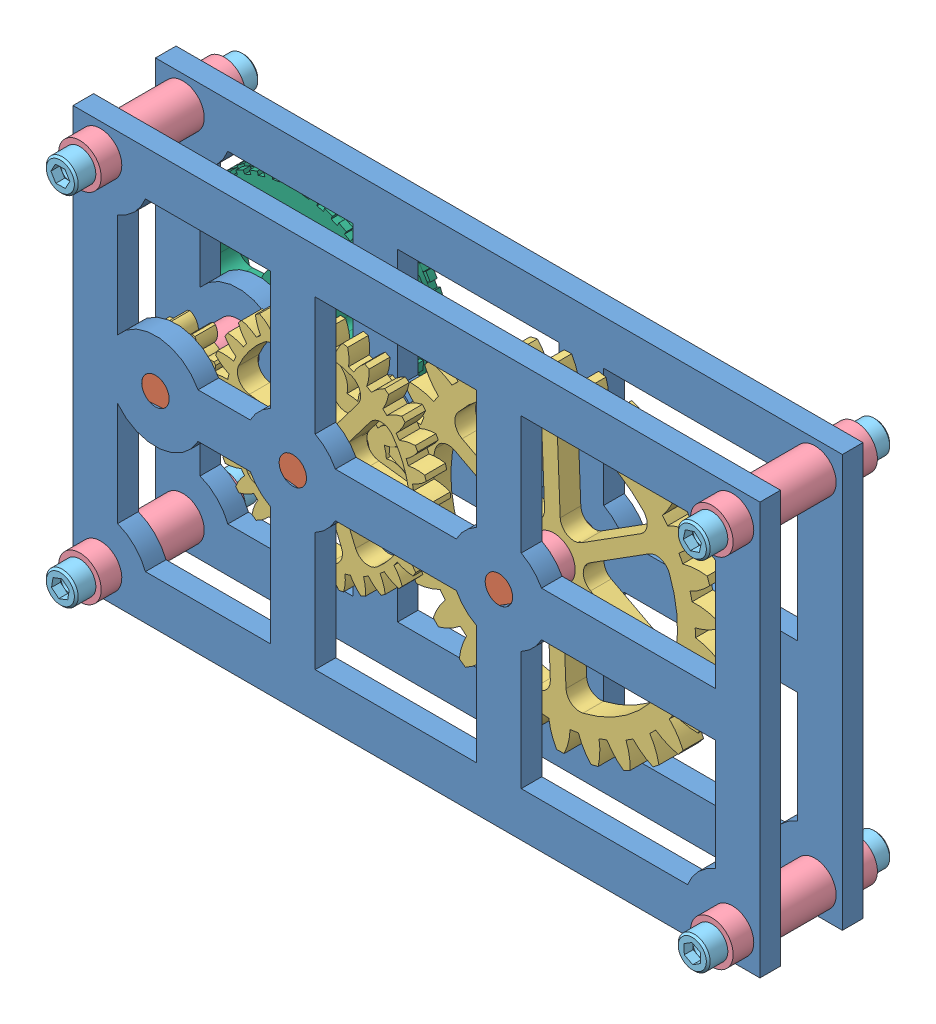
SolidWorks assembly gear_box, configuration Default. Lengths in mm.
Overall size (105.06 66.08 32.84).
42 component instances, 6 part files, 60 mates.
Components (placement in the parent):
- plate-1: plate [Default] at (41.197 56.7487 70.1164) size (100 60 3)
- assem_2-1: assem_2 [Default] at (31.1022 63.8399 66.8559) x (-0.992322 0.123679 0) z (0 0 1) size (32 31.89 15)
  - axle-1: axle [15mm] at (6.9674 8.0145 3.2605) size (4 3.72 15)
  - root_gear-1: root_gear [30T 1.0Mod] at (6.9674 8.0145 11.2605) size (32 31.89 3)
  - root_gear-2: root_gear [10T 1.5Mod] at (6.9674 8.0145 7.2605) size (18 17.3 3)
  - spacer-1: spacer [4.2mm ID 1L] at (6.9674 8.0145 6.2605) size (6.2 6.2 1)
  - spacer-2: spacer [4.2mm ID 1L] at (6.9674 8.0145 14.2605) x (0.300873 0.953664 0) z (0 0 1) size (6.2 6.2 1)
  - spacer-3: spacer [4.2mm ID 1L] at (6.9674 8.0145 10.2605) x (0.999497 0.031723 0) z (0 0 1) size (6.2 6.2 1)
- Assem3-1: Assem3 [Default] at (37.7796 60.6091 98.5469) x (0.845417 0.534107 0) z (0 0 -1) size (48 47.84 15)
  - spacer-1: spacer [4.2mm ID 1L] at (10.9723 11.4982 24.4305) x (0.97362 0.228174 0) z (0 0 1) size (6.2 6.2 1)
  - spacer-2: spacer [4.2mm ID 5L] at (10.9723 11.4982 16.4305) x (0.545669 0.838001 0) z (0 0 1) size (6.2 6.2 5)
  - root_gear-1: root_gear [30T 1.5Mod] at (10.9723 11.4982 21.4305) size (48 47.84 3)
  - axle-2: axle [15mm] at (10.9723 11.4982 13.4305) size (4 3.72 15)
- input_shaft-1: input_shaft [Default] at (12.1237 70.6083 53.7167) x (-0.998555 -0.053742 0) z (0 0 1) size (12 11.53 25)
  - axle-1: axle [25mm] at (9.6586 13.3599 6.3997) size (4 3.72 25)
  - spacer-2: spacer [4.2mm ID 5L] at (9.6586 13.3599 19.3997) size (6.2 6.2 5)
  - root_gear-1: root_gear [10T 1.0Mod] at (9.6586 13.3599 24.3997) size (12 11.53 3)
  - spacer-5: spacer [4.2mm ID 1L] at (9.6586 13.3599 27.3997) x (0.979964 -0.199174 0) z (0 0 1) size (6.2 6.2 1)
- socket head cap screw_ai-1: socket head cap screw_ai [HX-SHCS 0.112-40x0.375x0.375-N] at (87.197 82.7487 90.9612) x (0 0 -1) z (0.308765 -0.951138 0) size (12.37 4.65 4.65)
- socket head cap screw_ai-2: socket head cap screw_ai [HX-SHCS 0.112-40x0.375x0.375-N] at (87.197 30.7487 64.2716) x (0 0 1) z (0.223792 -0.974637 0) size (12.37 4.65 4.65)
- socket head cap screw_ai-3: socket head cap screw_ai [HX-SHCS 0.112-40x0.375x0.375-N] at (-4.803 30.7487 90.9612) x (0 0 -1) z (-0.353412 0.935468 0) size (12.37 4.65 4.65)
- socket head cap screw_ai-4: socket head cap screw_ai [HX-SHCS 0.112-40x0.375x0.375-N] at (87.197 30.7487 90.9612) x (0 0 -1) z (-0.533243 0.845962 0) size (12.37 4.65 4.65)
- socket head cap screw_ai-5: socket head cap screw_ai [HX-SHCS 0.112-40x0.375x0.375-N] at (-4.803 82.7487 90.9612) x (0 0 -1) z (0.029929 -0.999552 0) size (12.37 4.65 4.65)
- socket head cap screw_ai-6: socket head cap screw_ai [HX-SHCS 0.112-40x0.375x0.375-N] at (-4.803 30.7487 64.2716) x (0 0 1) z (-0.784512 -0.620114 0) size (12.37 4.65 4.65)
- socket head cap screw_ai-7: socket head cap screw_ai [HX-SHCS 0.112-40x0.375x0.375-N] at (-4.803 82.7487 64.2716) x (0 0 1) z (-0.730221 0.683211 0) size (12.37 4.65 4.65)
- socket head cap screw_ai-8: socket head cap screw_ai [HX-SHCS 0.112-40x0.375x0.375-N] at (87.197 82.7487 64.2716) x (0 0 1) z (0.910769 -0.412916 0) size (12.37 4.65 4.65)
- spacer-3: spacer [2.85mm ID] at (87.197 82.7487 73.1164) x (0.871909 0.489667 0) z (0 0 1) size (6.2 6.2 9)
- plate-2: plate [Default] at (41.197 56.7487 82.1164) size (100 60 3)
- spacer-4: spacer [2.85mm ID] at (-4.803 30.7487 73.1164) x (0.391403 0.92022 0) z (0 0 1) size (6.2 6.2 9)
- spacer-5: spacer [2.85mm ID] at (87.197 30.7487 73.1164) x (-0.230445 0.973085 0) z (0 0 1) size (6.2 6.2 9)
- spacer-8: spacer [2.85mm ID] at (-4.803 82.7487 73.1164) x (0.939947 -0.34132 0) z (0 0 1) size (6.2 6.2 9)
- spacer-9: spacer [3mm ID] at (87.197 82.7487 85.1164) size (6.2 6.2 3)
- spacer-10: spacer [3mm ID] at (87.197 30.7487 67.1164) size (6.2 6.2 3)
- spacer-11: spacer [3mm ID] at (87.197 30.7487 85.1164) size (6.2 6.2 3)
- spacer-12: spacer [3mm ID] at (87.197 82.7487 67.1164) x (0.999547 0.030106 0) z (0 0 1) size (6.2 6.2 3)
- spacer-13: spacer [3mm ID] at (-4.803 30.7487 85.1164) x (0.945923 -0.324392 0) z (0 0 1) size (6.2 6.2 3)
- spacer-14: spacer [3mm ID] at (-4.803 82.7487 67.1164) size (6.2 6.2 3)
- spacer-15: spacer [3mm ID] at (-4.803 82.7487 85.1164) size (6.2 6.2 3)
- spacer-16: spacer [3mm ID] at (-4.803 30.7487 67.1164) x (0.647249 0.762279 0) z (0 0 1) size (6.2 6.2 3)
- knob-1: knob [Default] at (3.197 56.7487 65.1164) x (0 0 -1) z (-0.998555 -0.053742 0) size (7 32 31.99)
- spacer-18: spacer [4.2mm ID 5L] at (3.197 56.7487 65.1164) x (0.94008 -0.340953 0) z (0 0 1) size (6.2 6.2 5)
- socket head cap screw_ai-14: socket head cap screw_ai [HX-SHCS 0.073-72x0.5625x0.5625-N] at (4.1569 38.914 63.1164) x (-0.053742 0.998555 0) z (-0.825125 -0.044408 -0.563202) size (16.14 3 3)
Mates (geometry in assembly coordinates):
- Concentric3: concentric anti-aligned: cylinder of plate-1 through (3.197 56.7487 70.1164) axis (0 0 1) radius 2; cylinder of input_shaft-1/axle-1 through (3.197 56.7487 85.1164) axis (0 0 -1) radius 2
- Coincident1: coincident anti-aligned: plane of plate-1 through (41.197 56.7487 73.1164) normal (0 0 1); plane of input_shaft-1/spacer-2 through (3.197 56.7487 73.1164) normal (0 0 -1)
- Concentric4: concentric anti-aligned: cylinder of plate-1 through (23.197 56.7487 70.1164) axis (0 0 1) radius 2; cylinder of assem_2-1/axle-1 through (23.197 56.7487 85.1164) axis (0 0 -1) radius 2
- Coincident2: coincident anti-aligned: plane of plate-1 through (41.197 56.7487 73.1164) normal (0 0 1); plane of assem_2-1/spacer-1 through (23.197 56.7487 73.1164) normal (0 0 -1)
- Coincident5: coincident anti-aligned: plane of plate-1 through (41.197 56.7487 73.1164) normal (0 0 1); plane of Assem3-1/spacer-1 through (53.197 56.7487 73.1164) normal (0 0 -1)
- Concentric7: concentric aligned: cylinder of plate-1 through (53.197 56.7487 70.1164) axis (0 0 1) radius 2; cylinder of Assem3-1/axle-2 through (53.197 56.7487 70.1164) axis (0 0 1) radius 2
- GearMate3: gear = 1 : 3 mm: cylinder of assem_2-1/axle-1 through (23.197 56.7487 85.1164) axis (0 0 -1) radius 2; cylinder of input_shaft-1/axle-1 through (3.197 56.7487 85.1164) axis (0 0 -1) radius 2
- GearMate4: gear = 1 : 3 mm: cylinder of Assem3-1/axle-2 through (53.197 56.7487 70.1164) axis (0 0 1) radius 2; cylinder of assem_2-1/axle-1 through (23.197 56.7487 85.1164) axis (0 0 -1) radius 2
- Concentric8: concentric anti-aligned: cylinder of plate-1 through (-4.803 30.7487 70.1164) axis (0 0 1) radius 1.5; cylinder of socket head cap screw_ai-6 through (-4.803 30.7487 32.5216) axis (0 0 -1) radius 1.4224
- Concentric9: concentric anti-aligned: cylinder of plate-1 through (87.197 30.7487 70.1164) axis (0 0 1) radius 1.5; cylinder of socket head cap screw_ai-2 through (87.197 30.7487 32.5216) axis (0 0 -1) radius 1.4224
- Concentric10: concentric anti-aligned: cylinder of plate-1 through (87.197 82.7487 70.1164) axis (0 0 1) radius 1.5; cylinder of socket head cap screw_ai-8 through (87.197 82.7487 32.5216) axis (0 0 -1) radius 1.4224
- Concentric11: concentric anti-aligned: cylinder of plate-1 through (87.197 82.7487 70.1164) axis (0 0 1) radius 1.5; cylinder of socket head cap screw_ai-8 through (87.197 82.7487 32.5216) axis (0 0 -1) radius 1.4224
- Concentric12: concentric anti-aligned: cylinder of plate-1 through (-4.803 82.7487 70.1164) axis (0 0 1) radius 1.5; cylinder of socket head cap screw_ai-7 through (-4.803 82.7487 32.5216) axis (0 0 -1) radius 1.4224
- Concentric15: concentric aligned: cylinder of socket head cap screw_ai-8 through (87.197 82.7487 32.5216) axis (0 0 -1) radius 1.4224; cylinder of spacer-3 through (87.197 82.7487 82.1164) axis (0 0 -1) radius 1.425
- Coincident12: coincident anti-aligned: plane of plate-1 through (41.197 56.7487 73.1164) normal (0 0 1); plane of spacer-3 through (87.197 82.7487 73.1164) normal (0 0 -1)
- Concentric18: concentric aligned: cylinder of Assem3-1/axle-2 through (53.197 56.7487 70.1164) axis (0 0 1) radius 2; cylinder of plate-2 through (53.197 56.7487 82.1164) axis (0 0 1) radius 2
- Concentric19: concentric aligned: cylinder of socket head cap screw_ai-1 through (87.197 82.7487 122.7112) axis (0 0 1) radius 1.4224; cylinder of plate-2 through (87.197 82.7487 82.1164) axis (0 0 1) radius 1.5
- Coincident14: coincident anti-aligned: circle of Assem3-1/axle-2; circle of plate-2
- Concentric20: concentric aligned: cylinder of socket head cap screw_ai-2 through (87.197 30.7487 32.5216) axis (0 0 -1) radius 1.4224; cylinder of spacer-5 through (87.197 30.7487 82.1164) axis (0 0 -1) radius 1.425
- Coincident15: coincident anti-aligned: plane of plate-1 through (41.197 56.7487 73.1164) normal (0 0 1); plane of spacer-5 through (87.197 30.7487 73.1164) normal (0 0 -1)
- Concentric21: concentric aligned: cylinder of socket head cap screw_ai-6 through (-4.803 30.7487 32.5216) axis (0 0 -1) radius 1.4224; cylinder of spacer-4 through (-4.803 30.7487 82.1164) axis (0 0 -1) radius 1.425
- Coincident16: coincident anti-aligned: plane of plate-1 through (41.197 56.7487 73.1164) normal (0 0 1); plane of spacer-4 through (-4.803 30.7487 73.1164) normal (0 0 -1)
- Concentric22: concentric aligned: cylinder of socket head cap screw_ai-7 through (-4.803 82.7487 32.5216) axis (0 0 -1) radius 1.4224; cylinder of spacer-8 through (-4.803 82.7487 82.1164) axis (0 0 -1) radius 1.425
- Coincident17: coincident anti-aligned: plane of plate-1 through (41.197 56.7487 73.1164) normal (0 0 1); plane of spacer-8 through (-4.803 82.7487 73.1164) normal (0 0 -1)
- Concentric23: concentric aligned: cylinder of socket head cap screw_ai-8 through (87.197 82.7487 32.5216) axis (0 0 -1) radius 1.4224; cylinder of spacer-12 through (87.197 82.7487 70.1164) axis (0 0 -1) radius 1.5
- Coincident18: coincident anti-aligned: plane of plate-1 through (41.197 56.7487 70.1164) normal (0 0 -1); circle of spacer-12
- Coincident19: coincident aligned: plane of socket head cap screw_ai-8 through (86.2374 80.632 67.1164) normal (0 0 1); circle of spacer-12
- Concentric25: concentric anti-aligned: cylinder of socket head cap screw_ai-1 through (87.197 82.7487 122.7112) axis (0 0 1) radius 1.4224; cylinder of spacer-9 through (87.197 82.7487 88.1164) axis (0 0 -1) radius 1.5
- Coincident20: coincident anti-aligned: plane of socket head cap screw_ai-1 through (89.4076 83.4663 88.1164) normal (0 0 -1); plane of spacer-9 through (87.197 82.7487 88.1164) normal (0 0 1)
- Coincident21: coincident anti-aligned: plane of plate-2 through (41.197 56.7487 85.1164) normal (0 0 1); plane of spacer-9 through (87.197 82.7487 85.1164) normal (0 0 -1)
- Concentric26: concentric anti-aligned: cylinder of socket head cap screw_ai-1 through (87.197 82.7487 122.7112) axis (0 0 1) radius 1.4224; cylinder of spacer-3 through (87.197 82.7487 82.1164) axis (0 0 -1) radius 1.425
- Concentric27: concentric aligned: cylinder of socket head cap screw_ai-2 through (87.197 30.7487 32.5216) axis (0 0 -1) radius 1.4224; cylinder of spacer-10 through (87.197 30.7487 70.1164) axis (0 0 -1) radius 1.5
- Coincident22: coincident anti-aligned: plane of socket head cap screw_ai-2 through (84.9319 30.2286 67.1164) normal (0 0 1); plane of spacer-10 through (87.197 30.7487 67.1164) normal (0 0 -1)
- Coincident23: coincident anti-aligned: plane of plate-1 through (41.197 56.7487 70.1164) normal (0 0 -1); plane of spacer-10 through (87.197 30.7487 70.1164) normal (0 0 1)
- Concentric28: concentric aligned: cylinder of socket head cap screw_ai-4 through (87.197 30.7487 122.7112) axis (0 0 1) radius 1.4224; cylinder of plate-2 through (87.197 30.7487 82.1164) axis (0 0 1) radius 1.5
- Concentric29: concentric anti-aligned: cylinder of socket head cap screw_ai-4 through (87.197 30.7487 122.7112) axis (0 0 1) radius 1.4224; cylinder of spacer-11 through (87.197 30.7487 88.1164) axis (0 0 -1) radius 1.5
- Coincident24: coincident aligned: circle of socket head cap screw_ai-4; plane of spacer-11 through (87.197 30.7487 88.1164) normal (0 0 1)
- Concentric30: concentric aligned: cylinder of socket head cap screw_ai-4 through (87.197 30.7487 122.7112) axis (0 0 1) radius 1.4224; cylinder of plate-2 through (87.197 30.7487 82.1164) axis (0 0 1) radius 1.5
- Coincident25: coincident anti-aligned: plane of plate-2 through (41.197 56.7487 85.1164) normal (0 0 1); plane of spacer-11 through (87.197 30.7487 85.1164) normal (0 0 -1)
- Concentric31: concentric aligned: cylinder of socket head cap screw_ai-3 through (-4.803 30.7487 122.7112) axis (0 0 1) radius 1.4224; cylinder of plate-2 through (-4.803 30.7487 82.1164) axis (0 0 1) radius 1.5
- Concentric32: concentric anti-aligned: cylinder of socket head cap screw_ai-3 through (-4.803 30.7487 122.7112) axis (0 0 1) radius 1.4224; cylinder of spacer-13 through (-4.803 30.7487 88.1164) axis (0 0 -1) radius 1.5
- Coincident26: coincident anti-aligned: plane of socket head cap screw_ai-3 through (-6.9771 29.9273 88.1164) normal (0 0 -1); plane of spacer-13 through (-4.803 30.7487 88.1164) normal (0 0 1)
- Concentric33: concentric aligned: cylinder of socket head cap screw_ai-3 through (-4.803 30.7487 122.7112) axis (0 0 1) radius 1.4224; cylinder of plate-2 through (-4.803 30.7487 82.1164) axis (0 0 1) radius 1.5
- Coincident27: coincident anti-aligned: plane of plate-2 through (41.197 56.7487 85.1164) normal (0 0 1); plane of spacer-13 through (-4.803 30.7487 85.1164) normal (0 0 -1)
- Concentric34: concentric aligned: cylinder of socket head cap screw_ai-5 through (-4.803 82.7487 122.7112) axis (0 0 1) radius 1.4224; cylinder of plate-2 through (-4.803 82.7487 82.1164) axis (0 0 1) radius 1.5
- Concentric35: concentric anti-aligned: cylinder of socket head cap screw_ai-5 through (-4.803 82.7487 122.7112) axis (0 0 1) radius 1.4224; cylinder of spacer-15 through (-4.803 82.7487 88.1164) axis (0 0 -1) radius 1.5
- Coincident28: coincident anti-aligned: plane of socket head cap screw_ai-5 through (-2.4799 82.8182 88.1164) normal (0 0 -1); plane of spacer-15 through (-4.803 82.7487 88.1164) normal (0 0 1)
- Coincident29: coincident anti-aligned: plane of plate-2 through (41.197 56.7487 85.1164) normal (0 0 1); plane of spacer-15 through (-4.803 82.7487 85.1164) normal (0 0 -1)
- Coincident30: coincident aligned: plane of socket head cap screw_ai-7 through (-3.2151 84.4458 67.1164) normal (0 0 1); circle of spacer-14
- Concentric36: concentric aligned: cylinder of socket head cap screw_ai-7 through (-4.803 82.7487 32.5216) axis (0 0 -1) radius 1.4224; cylinder of spacer-14 through (-4.803 82.7487 70.1164) axis (0 0 -1) radius 1.5
- Coincident31: coincident anti-aligned: plane of plate-1 through (41.197 56.7487 70.1164) normal (0 0 -1); plane of spacer-14 through (-4.803 82.7487 70.1164) normal (0 0 1)
- Concentric37: concentric aligned: cylinder of socket head cap screw_ai-6 through (-4.803 30.7487 32.5216) axis (0 0 -1) radius 1.4224; cylinder of spacer-16 through (-4.803 30.7487 70.1164) axis (0 0 -1) radius 1.5
- Coincident32: coincident aligned: circle of socket head cap screw_ai-6; plane of spacer-16 through (-4.803 30.7487 67.1164) normal (0 0 -1)
- Coincident33: coincident anti-aligned: plane of plate-1 through (41.197 56.7487 70.1164) normal (0 0 -1); circle of spacer-16
- Concentric38: concentric anti-aligned: cylinder of input_shaft-1/axle-1 through (3.197 56.7487 85.1164) axis (0 0 -1) radius 2; cylinder of knob-1 through (3.197 56.7487 65.1164) axis (0 0 1) radius 2
- Coincident34: coincident aligned: circle of input_shaft-1/axle-1; circle of knob-1
- Concentric39: concentric aligned: cylinder of input_shaft-1/axle-1 through (3.197 56.7487 85.1164) axis (0 0 -1) radius 2; cylinder of spacer-18 through (3.197 56.7487 70.1164) axis (0 0 -1) radius 2.1
- Coincident35: coincident anti-aligned: plane of plate-1 through (41.197 56.7487 70.1164) normal (0 0 -1); circle of spacer-18
- Concentric43: concentric anti-aligned: cylinder of knob-1 through (3.197 56.7487 63.1164) axis (-0.053742 0.998555 0) radius 1.5; cylinder of socket head cap screw_ai-14 through (5.8632 7.2099 63.1164) axis (0.053742 -0.998555 0) radius 0.9271
- Coincident38: coincident anti-aligned: plane of input_shaft-1/axle-1 through (4.3106 55.0874 85.1164) normal (0.053742 -0.998555 0); plane of socket head cap screw_ai-14 through (3.6929 55.0541 62.5235) normal (-0.053742 0.998555 0)
